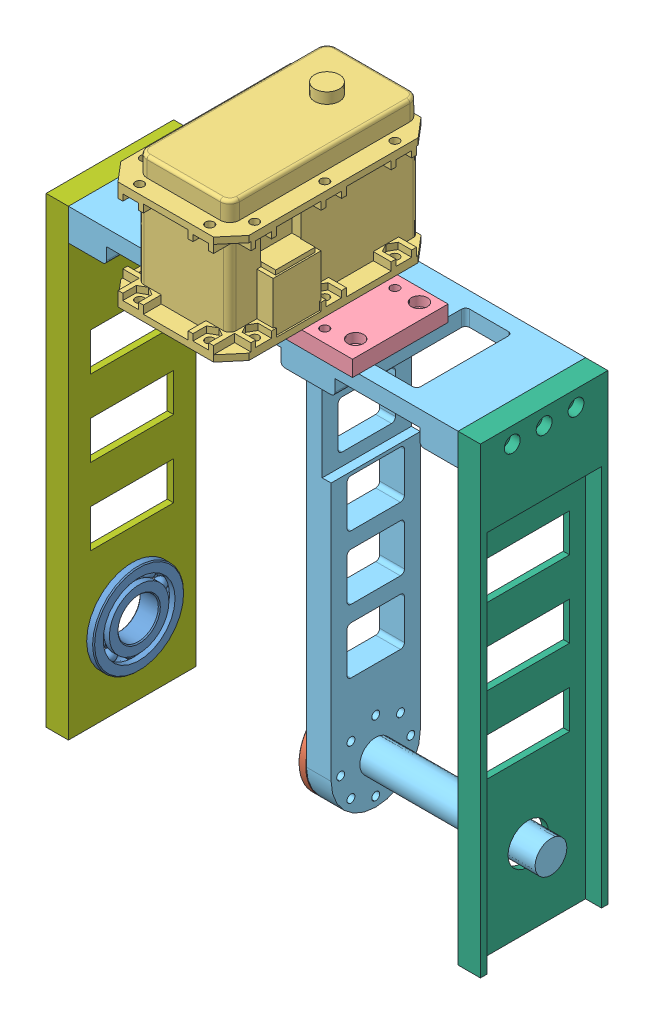
SolidWorks assembly Link3, configuration Default. Lengths in mm.
Overall size (138.43 199.5 70.6).
7 component instances, 7 part files, 17 mates.
Components (placement in the parent):
- BallBearing25-1: BallBearing25 [60355K505] at (-84.7268 -57.5427 22.4713) x (0 0 -1) z (1 0 0) size (28.57 28.57 6.35)
- HN05-N101-1: HN05-N101 [Default] at (-17.5468 -57.5427 22.4713) x (0 0 -1) z (0 -1 0) size (28 5.3 28)
- EX-106+-1: EX-106+ [Default] at (-22.5868 91.5573 22.4713) x (1 0 0) z (0 1 0) size (40.2 65.92 50.9)
- adapter_ex106-1: adapter_ex106 [Default] at (-52.5868 63.5573 44.4713) size (60 5 30)
- Motor2Frame_HN05-N101_bug_fixed-1: Motor2Frame_HN05-N101_bug_fixed [Default] at (-83.7268 63.5573 2.4713) x (1 0 0) z (0 -1 0) size (131.43 40 135.1)
- Motor2Frame_Side1-1: Motor2Frame_Side1 [Default] at (38.5532 -81.5427 42.4713) x (0 0 -1) z (1 0 0) size (40 145.1 7)
- Motor2Frame_Side2-1: Motor2Frame_Side2 [Default] at (-83.7268 -81.5427 2.4713) x (0 0 1) z (-1 0 0) size (40 145.1 7)
Mates (geometry in assembly coordinates):
- Concentric1: concentric: circle of adapter_ex106-1; circle of Motor2Frame_HN05-N101_bug_fixed-1
- Concentric2: concentric: circle of adapter_ex106-1; circle of Motor2Frame_HN05-N101_bug_fixed-1
- Coincident1: coincident anti-aligned: plane of adapter_ex106-1 through (-52.5868 63.5573 44.4713) normal (0 -1 0); plane of Motor2Frame_HN05-N101_bug_fixed-1 through (-83.7268 63.5573 2.4713) normal (0 1 0)
- Concentric3: concentric: circle of EX-106+-1; circle of adapter_ex106-1
- Concentric4: concentric: circle of EX-106+-1; circle of adapter_ex106-1
- Coincident2: coincident anti-aligned: plane of EX-106+-1 through (-22.5868 68.5573 22.4713) normal (0 -1 0); plane of adapter_ex106-1 through (-52.5868 68.5573 44.4713) normal (0 1 0)
- Concentric5: concentric: circle of Motor2Frame_HN05-N101_bug_fixed-1; circle of Motor2Frame_Side1-1
- Concentric6: concentric: circle of Motor2Frame_HN05-N101_bug_fixed-1; circle of Motor2Frame_Side1-1
- Coincident3: coincident anti-aligned: plane of Motor2Frame_HN05-N101_bug_fixed-1 through (38.5532 53.5573 2.4713) normal (1 0 0); plane of Motor2Frame_Side1-1 through (38.5532 -81.5427 42.4713) normal (-1 0 0)
- Concentric7: concentric: circle of Motor2Frame_HN05-N101_bug_fixed-1; circle of Motor2Frame_Side2-1
- Concentric8: concentric: circle of Motor2Frame_HN05-N101_bug_fixed-1; circle of Motor2Frame_Side2-1
- Coincident4: coincident anti-aligned: plane of Motor2Frame_HN05-N101_bug_fixed-1 through (-83.7268 53.5573 2.4713) normal (-1 0 0); plane of Motor2Frame_Side2-1 through (-83.7268 -81.5427 2.4713) normal (1 0 0)
- Concentric9: concentric: circle of HN05-N101-1; circle of Motor2Frame_HN05-N101_bug_fixed-1
- Concentric10: concentric: circle of HN05-N101-1; circle of Motor2Frame_HN05-N101_bug_fixed-1
- Coincident5: coincident anti-aligned: plane of HN05-N101-1 through (-15.0468 -57.5427 22.4713) normal (1 0 0); plane of Motor2Frame_HN05-N101_bug_fixed-1 through (-15.0468 -57.5427 36.4713) normal (-1 0 0)
- Concentric11: concentric: circle of BallBearing25-1; circle of Motor2Frame_Side2-1
- Distance1: distance = 2.175 mm aligned: plane of Motor2Frame_Side2-1 through (-85.7268 -81.5427 2.4713) normal (-1 0 0); plane of BallBearing25-1 through (-87.9018 -43.5727 22.4713) normal (-1 0 0)
